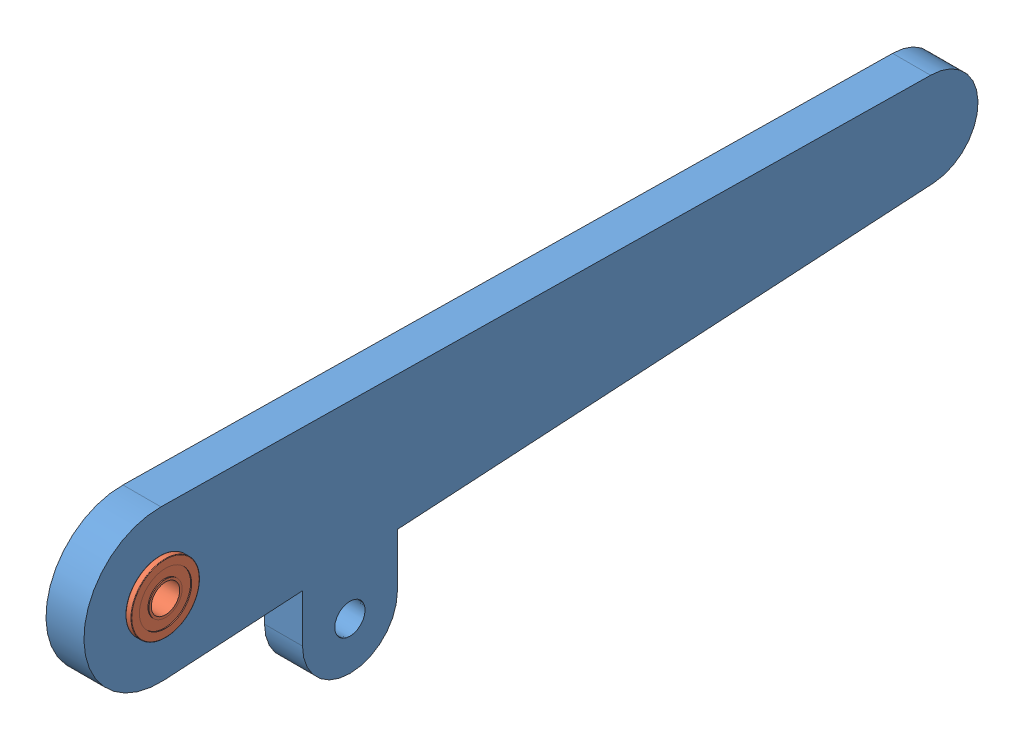
SolidWorks assembly Spider_lowerleg, configuration Default. Lengths in mm.
Overall size (5.2 25.17 94.25).
3 component instances, 2 part files, 4 mates.
Components (placement in the parent):
- SLS_leg_lower-1: SLS_leg_lower [Default] at origin size (4 25.17 94.25)
- MF63zz 3x6x2.5mm Flanged Bearing.step-1: MF63zz 3x6x2.5mm Flanged Bearing.step [Default] at (4.6 0 0) x (0 0 -1) z (-1 0 0) size (7.2 7.2 2.5)
- MF63zz 3x6x2.5mm Flanged Bearing.step-2: MF63zz 3x6x2.5mm Flanged Bearing.step [Default] at (-0.6 0 0) x (0 0 -1) z (1 0 0) size (7.2 7.2 2.5)
Mates (geometry in assembly coordinates):
- Concentric1: concentric: cylinder of SLS_leg_lower-1 through (4 0 0) axis (-1 0 0) radius 3; cylinder of MF63zz 3x6x2.5mm Flanged Bearing.step-2 through (0.95 0 0) axis (-1 0 0) radius 3
- Coincident1: coincident anti-aligned: plane of SLS_leg_lower-1 through (0 0 0) normal (-1 0 0); plane of MF63zz 3x6x2.5mm Flanged Bearing.step-2 through (0 0 3.6) normal (1 0 0)
- Concentric2: concentric: cylinder of SLS_leg_lower-1 through (4 0 0) axis (-1 0 0) radius 3; cylinder of MF63zz 3x6x2.5mm Flanged Bearing.step-1 through (3.05 0 0) axis (1 0 0) radius 3
- Coincident2: coincident anti-aligned: plane of SLS_leg_lower-1 through (4 0 0) normal (1 0 0); plane of MF63zz 3x6x2.5mm Flanged Bearing.step-1 through (4 0 3.6) normal (-1 0 0)
